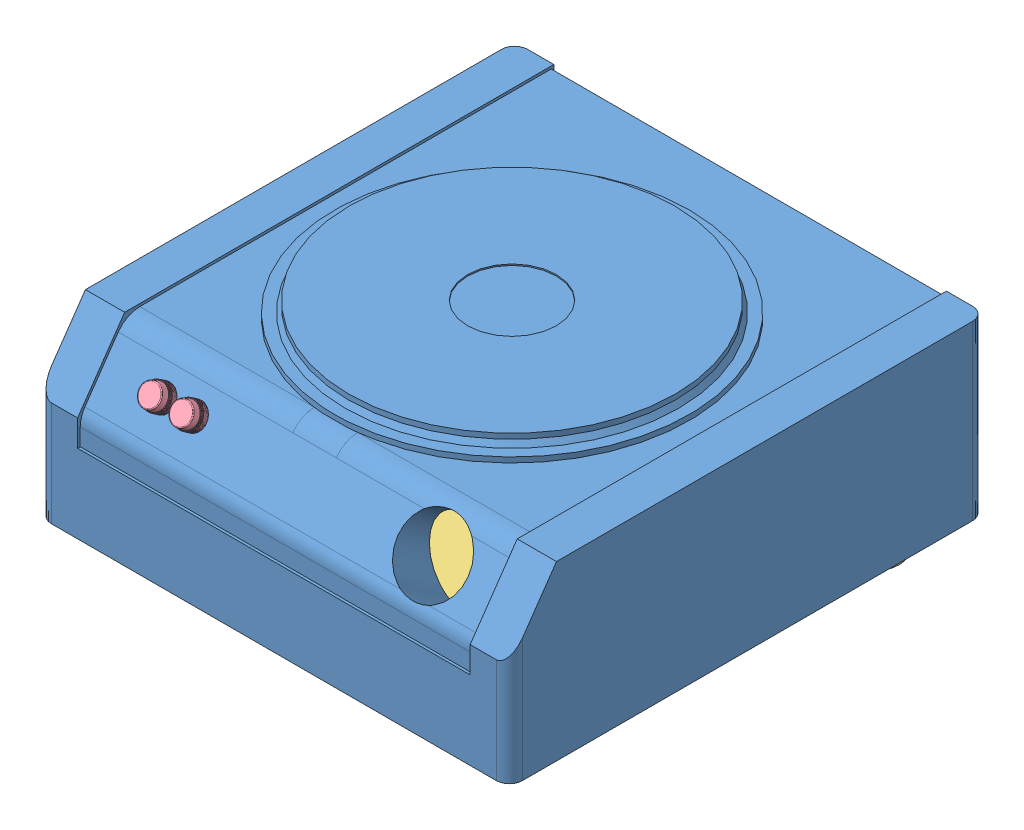
SolidWorks assembly Assem1, configuration Default. Lengths in mm.
Overall size (180 82 188.24).
5 component instances, 4 part files, 9 mates.
Components (placement in the parent):
- Part1-1: Part1 [Default] at (101.4857 116.75 115.3575) size (180 71 182)
- AC_Power_Socket-3_pin_250V_10A_AC-17-2: AC_Power_Socket-3_pin_250V_10A_AC-17 [Default] at (81.3517 114.5291 46.7098) x (-1 0 0) z (0 0 -1) size (66.3 32.3 35.64)
- cover-1: cover [Default] at (-26.0941 68.3791 225.2167) x (0 0 -1) z (1 0 0) size (176.9 14 176.52)
- PanelMountIndicatorLight-1: PanelMountIndicatorLight [Default] at (9.5649 124.6985 222.6423) x (1 0 0) z (0 0.5694 0.822061) size (9.49 9.49 17.46)
- PanelMountIndicatorLight-2: PanelMountIndicatorLight [Default] at (21.6088 124.6985 222.6423) x (1 0 0) z (0 0.5694 0.822061) size (9.49 9.49 17.46)
Mates (geometry in assembly coordinates):
- Coincident3: coincident anti-aligned: plane of Part1-1 through (62.1428 115.8791 46.7098) normal (0 0 -1); plane of AC_Power_Socket-3_pin_250V_10A_AC-17-2 through (108.5017 114.5291 46.7098) normal (0 0 1)
- Coincident4: coincident anti-aligned: plane of Part1-1 through (101.4857 98.3791 115.3575) normal (0 1 0); plane of AC_Power_Socket-3_pin_250V_10A_AC-17-2 through (103.3216 98.3791 43.9098) normal (0 -1 0)
- Coincident5: coincident anti-aligned: plane of Part1-1 through (101.4857 71.3791 115.3575) normal (0 -1 0); plane of cover-1 through (-26.0941 71.3791 225.2167) normal (0 1 0)
- Coincident6: coincident anti-aligned: plane of Part1-1 through (-26.0941 71.3791 225.2167) normal (0 0 -1); plane of cover-1 through (-26.0941 71.3791 225.2167) normal (0 0 1)
- Coincident7: coincident anti-aligned: plane of Part1-1 through (-26.0941 131.3791 205.7968) normal (1 0 0); plane of cover-1 through (-26.0941 71.3791 225.2167) normal (-1 0 0)
- Coincident8: coincident: plane of Part1-1 through (-60.8572 108.0855 226.7098) normal (0 0.5694 0.822061); plane of PanelMountIndicatorLight-1 through (52.8232 86.4707 241.6813) normal (0 -0.5694 -0.822061)
- Concentric1: concentric anti-aligned: circle of Part1-1; circle of PanelMountIndicatorLight-1
- Coincident9: coincident: plane of Part1-1 through (-60.8572 108.0855 226.7098) normal (0 0.5694 0.822061); plane of PanelMountIndicatorLight-2 through (-13.0811 165.0844 187.2296) normal (0 -0.5694 -0.822061)
- Concentric2: concentric aligned: circle of Part1-1; circle of PanelMountIndicatorLight-2
